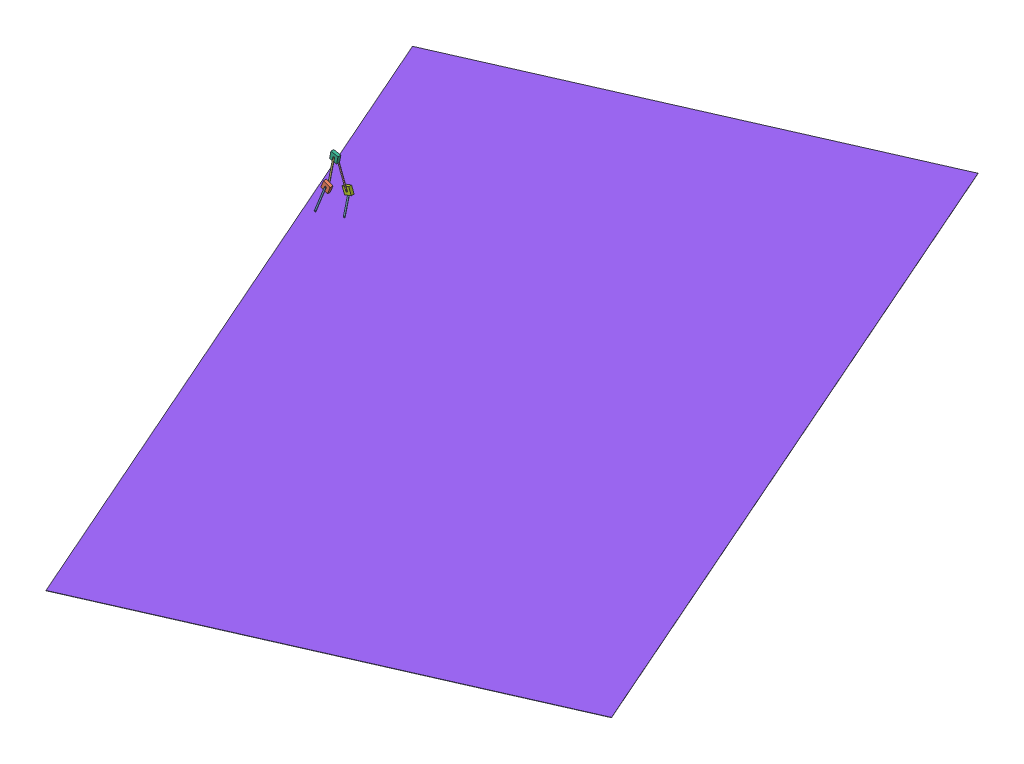
SolidWorks assembly link, configuration Default. Lengths in mm.
Overall size (4759.65 400.86 5784.79).
8 component instances, 8 part files, 20 mates.
Components (placement in the parent):
- pend-1: pend [Default] at (90.2583 333.8485 127.0121) x (0.929083 -0.369871 0) z (0 0 1) size (10 200 2)
- mass-1: mass [Default] at (125.3961 422.1114 107.0121) x (0.369871 0.929083 0) z (0 0 1) size (50 50 20)
- pend1-1: pend1 [Default] at (143.4098 515.3879 105.0121) x (0.981858 -0.189618 0) z (0 0 1) size (10 200 2)
- pend 3-1: pend 3 [Default] at (195.4103 519.952 83.0121) x (0.933815 0.357757 0) z (0 0 1) size (10 200 2)
- pend 4-1: pend 4 [Default] at (210.6408 338.1096 61.0121) x (0.980316 -0.197436 0) z (0 0 1) size (10 200 2)
- mass2-1: mass2 [Default] at (161.4234 608.6644 85.0121) x (0.981858 -0.189618 0) z (0 0 1) size (50 50 20)
- mass3-1: mass3 [Default] at (229.3972 431.2396 63.0121) x (0.933815 0.357757 0) z (0 0 1) size (50 50 20)
- platform-1: platform [Default] at (1772.6307 239.0909 470.0168) x (0.402741 0 0.915314) z (0 -1 0) size (5000 3000 2)
Mates (geometry in assembly coordinates):
- Concentric1: concentric: cylinder of pend-1 through (153.9219 412.5655 129.0121) axis (0 0 -1) radius 2; cylinder of mass-1 through (153.9219 412.5655 127.0121) axis (0 0 -1) radius 2
- Coincident1: coincident: plane of pend-1 through (112.8402 326.9075 127.0121) normal (0 0 -1); plane of mass-1 through (153.9219 412.5655 127.0121) normal (0 0 1)
- Parallel1: parallel: plane of pend-1 through (151.5758 419.236 129.0121) normal (-0.901663 0.432438 0); plane of mass-1 through (120.5693 400.8349 127.0121) normal (-0.901663 0.432438 0)
- Concentric8: concentric: cylinder of mass-1 through (153.9219 412.5655 127.0121) axis (0 0 -1) radius 2; cylinder of pend1-1 through (153.9219 412.5655 107.0121) axis (0 0 -1) radius 2
- Coincident9: coincident: plane of mass-1 through (153.9219 412.5655 107.0121) normal (0 0 -1); plane of pend1-1 through (178.2617 504.3945 107.0121) normal (0 0 1)
- Concentric13: concentric: cylinder of pend1-1 through (202.6015 596.2236 107.0121) axis (0 0 -1) radius 2; cylinder of mass2-1 through (202.6015 596.2236 105.0121) axis (0 0 -1) radius 2
- Coincident16: coincident: plane of pend1-1 through (178.2617 504.3945 105.0121) normal (0 0 -1); plane of mass2-1 through (202.6015 596.2236 105.0121) normal (0 0 1)
- Parallel4: parallel: plane of pend1-1; plane of mass2-1
- Concentric14: concentric: cylinder of pend 3-1 through (202.6015 596.2236 85.0121) axis (0 0 -1) radius 2; cylinder of mass2-1 through (202.6015 596.2236 105.0121) axis (0 0 -1) radius 2
- Coincident18: coincident: plane of pend 3-1 through (230.4525 505.3978 85.0121) normal (0 0 1); plane of mass2-1 through (202.6015 596.2236 85.0121) normal (0 0 -1)
- Concentric15: concentric: cylinder of pend 3-1 through (258.3035 414.572 85.0121) axis (0 0 -1) radius 2; cylinder of mass3-1 through (258.3035 414.572 83.0121) axis (0 0 -1) radius 2
- Coincident19: coincident: plane of pend 3-1 through (230.4525 505.3978 83.0121) normal (0 0 -1); plane of mass3-1 through (258.3035 414.572 83.0121) normal (0 0 1)
- Concentric16: concentric: cylinder of pend 4-1 through (258.3035 414.572 63.0121) axis (0 0 -1) radius 2; cylinder of mass3-1 through (258.3035 414.572 83.0121) axis (0 0 -1) radius 2
- Coincident20: coincident: plane of pend 4-1 through (233.2327 322.9399 63.0121) normal (0 0 1); plane of mass3-1 through (258.3035 414.572 63.0121) normal (0 0 -1)
- Parallel5: parallel: plane of pend 3-1 through (205.916 602.4697 85.0121) normal (0.956061 0.293169 0); plane of mass3-1 through (274.8758 445.8028 83.0121) normal (0.956061 0.293169 0)
- Coincident22: coincident: plane of pend 3-1 through (230.4525 505.3978 83.0121) normal (0 0 -1); plane of mass3-1 through (258.3035 414.572 83.0121) normal (0 0 1)
- Coincident23: coincident: plane of pend 4-1 through (233.2327 322.9399 63.0121) normal (0 0 1); plane of mass3-1 through (258.3035 414.572 63.0121) normal (0 0 -1)
- Parallel6: parallel: plane of platform-1 through (1772.6307 225.1655 470.0168) normal (0 1 0); plane of assembly through (0 0 0) normal (0 1 0)
- Coincident26: coincident: line of pend 4-1 through (195.7988 239.0909 63.0121) axis (0 0 -1); plane of platform-1 through (1772.6307 239.0909 470.0168) normal (0 1 0)
- Coincident27: coincident: line of pend-1 through (57.9166 239.0909 129.0121) axis (0 0 -1); plane of platform-1 through (1772.6307 239.0909 470.0168) normal (0 1 0)
